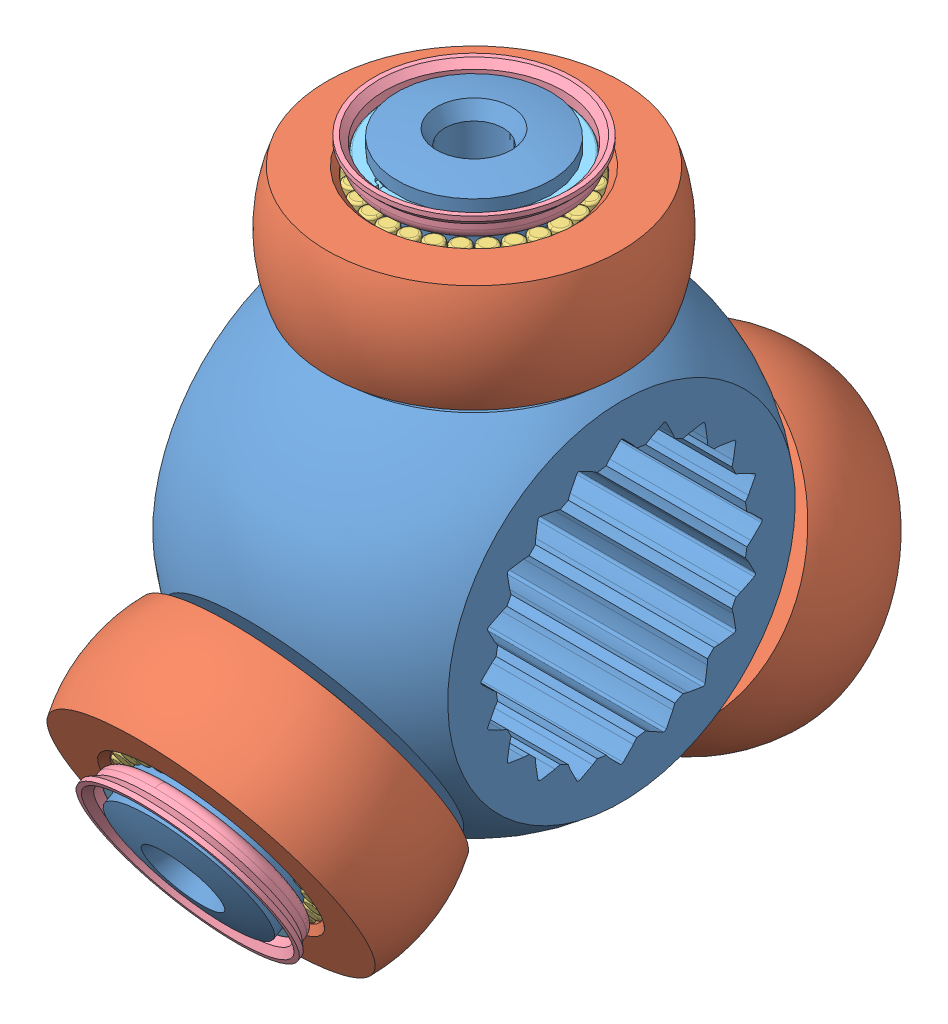
SolidWorks assembly Taylor INV-02002011, configuration Default. Lengths in mm.
Overall size (27.63 50.78 55.51).
97 component instances, 6 part files, 0 mates.
Components (placement in the parent):
- INV-020020111-1: INV-020020111 [Default] at origin size (24 46.21 53.88)
- INV-020020112-1: INV-020020112 [Default] at (0 20.32 0) x (0 -1 0) z (0 0 1) size (8.76 25.45 25.45)
- INV-020020116-1: INV-020020116 [Default] at (0 20.32 7.0097) x (0 0 1) z (-1 0 0) size (1.5 7.8 1.5)
- INV-020020116-2: INV-020020116 [Default] at (1.5598 20.32 6.834) x (0.222521 0 0.974928) z (-0.974928 0 0.222521) size (1.5 7.8 1.5)
- INV-020020116-3: INV-020020116 [Default] at (3.0414 20.32 6.3155) x (0.433884 0 0.900969) z (-0.900969 0 0.433884) size (1.5 7.8 1.5)
- INV-020020116-4: INV-020020116 [Default] at (4.3705 20.32 5.4804) x (0.62349 0 0.781831) z (-0.781831 0 0.62349) size (1.5 7.8 1.5)
- INV-020020116-5: INV-020020116 [Default] at (5.4804 20.32 4.3705) x (0.781831 0 0.62349) z (-0.62349 0 0.781831) size (1.5 7.8 1.5)
- INV-020020116-6: INV-020020116 [Default] at (6.3155 20.32 3.0414) x (0.900969 0 0.433884) z (-0.433884 0 0.900969) size (1.5 7.8 1.5)
- INV-020020116-7: INV-020020116 [Default] at (6.834 20.32 1.5598) x (0.974928 0 0.222521) z (-0.222521 0 0.974928) size (1.5 7.8 1.5)
- INV-020020116-8: INV-020020116 [Default] at (7.0097 20.32 0) size (1.5 7.8 1.5)
- INV-020020116-9: INV-020020116 [Default] at (6.834 20.32 -1.5598) x (0.974928 0 -0.222521) z (0.222521 0 0.974928) size (1.5 7.8 1.5)
- INV-020020116-10: INV-020020116 [Default] at (6.3155 20.32 -3.0414) x (0.900969 0 -0.433884) z (0.433884 0 0.900969) size (1.5 7.8 1.5)
- INV-020020116-11: INV-020020116 [Default] at (5.4804 20.32 -4.3705) x (0.781831 0 -0.62349) z (0.62349 0 0.781831) size (1.5 7.8 1.5)
- INV-020020116-12: INV-020020116 [Default] at (4.3705 20.32 -5.4804) x (0.62349 0 -0.781831) z (0.781831 0 0.62349) size (1.5 7.8 1.5)
- INV-020020116-13: INV-020020116 [Default] at (3.0414 20.32 -6.3155) x (0.433884 0 -0.900969) z (0.900969 0 0.433884) size (1.5 7.8 1.5)
- INV-020020116-14: INV-020020116 [Default] at (1.5598 20.32 -6.834) x (0.222521 0 -0.974928) z (0.974928 0 0.222521) size (1.5 7.8 1.5)
- INV-020020116-15: INV-020020116 [Default] at (0 20.32 -7.0097) x (0 0 -1) z (1 0 0) size (1.5 7.8 1.5)
- INV-020020116-16: INV-020020116 [Default] at (-1.5598 20.32 -6.834) x (-0.222521 0 -0.974928) z (0.974928 0 -0.222521) size (1.5 7.8 1.5)
- INV-020020116-17: INV-020020116 [Default] at (-3.0414 20.32 -6.3155) x (-0.433884 0 -0.900969) z (0.900969 0 -0.433884) size (1.5 7.8 1.5)
- INV-020020116-18: INV-020020116 [Default] at (-4.3705 20.32 -5.4804) x (-0.62349 0 -0.781831) z (0.781831 0 -0.62349) size (1.5 7.8 1.5)
- INV-020020116-19: INV-020020116 [Default] at (-5.4804 20.32 -4.3705) x (-0.781831 0 -0.62349) z (0.62349 0 -0.781831) size (1.5 7.8 1.5)
- INV-020020116-20: INV-020020116 [Default] at (-6.3155 20.32 -3.0414) x (-0.900969 0 -0.433884) z (0.433884 0 -0.900969) size (1.5 7.8 1.5)
- INV-020020116-21: INV-020020116 [Default] at (-6.834 20.32 -1.5598) x (-0.974928 0 -0.222521) z (0.222521 0 -0.974928) size (1.5 7.8 1.5)
- INV-020020116-22: INV-020020116 [Default] at (-7.0097 20.32 0) x (-1 0 0) z (0 0 -1) size (1.5 7.8 1.5)
- INV-020020116-23: INV-020020116 [Default] at (-6.834 20.32 1.5598) x (-0.974928 0 0.222521) z (-0.222521 0 -0.974928) size (1.5 7.8 1.5)
- INV-020020116-24: INV-020020116 [Default] at (-6.3155 20.32 3.0414) x (-0.900969 0 0.433884) z (-0.433884 0 -0.900969) size (1.5 7.8 1.5)
- INV-020020116-25: INV-020020116 [Default] at (-5.4804 20.32 4.3705) x (-0.781831 0 0.62349) z (-0.62349 0 -0.781831) size (1.5 7.8 1.5)
- INV-020020116-26: INV-020020116 [Default] at (-4.3705 20.32 5.4804) x (-0.62349 0 0.781831) z (-0.781831 0 -0.62349) size (1.5 7.8 1.5)
- INV-020020116-27: INV-020020116 [Default] at (-3.0414 20.32 6.3155) x (-0.433884 0 0.900969) z (-0.900969 0 -0.433884) size (1.5 7.8 1.5)
- INV-020020116-28: INV-020020116 [Default] at (-1.5598 20.32 6.834) x (-0.222521 0 0.974928) z (-0.974928 0 -0.222521) size (1.5 7.8 1.5)
- INV-020020113-1: INV-020020113 [Default] at (0 24.7396 0) size (16.26 2.16 16.26)
- WS_50-1-1: WS_50-1 [Default] at (0 25.4381 0) size (27.63 0.71 15.46)
- INV-020020116-29: INV-020020116 [Default] at (0 -4.0894 -21.1025) x (0 0.866025 -0.5) z (-1 0 0) size (1.5 7.8 1.5)
- INV-020020116-30: INV-020020116 [Default] at (0 -16.2306 14.0928) x (0 -0.866025 -0.5) z (-1 0 0) size (1.5 7.8 1.5)
- INV-020020113-2: INV-020020113 [Default] at (0 -12.3698 -21.4251) x (1 0 0) z (0 0.866025 -0.5) size (16.26 2.16 16.26)
- INV-020020113-3: INV-020020113 [Default] at (0 -12.3698 21.4251) x (1 0 0) z (0 -0.866025 -0.5) size (16.26 2.16 16.26)
- WS_50-1-2: WS_50-1 [Default] at (0 -12.7191 -22.03) x (1 0 0) z (0 0.866025 -0.5) size (27.63 0.71 15.46)
- WS_50-1-3: WS_50-1 [Default] at (0 -12.7191 22.03) x (1 0 0) z (0 -0.866025 -0.5) size (27.63 0.71 15.46)
- INV-020020116-31: INV-020020116 [Default] at (1.5598 -4.2416 -21.0146) x (0.222521 0.844312 -0.487464) z (-0.974928 0.192709 -0.11126) size (1.5 7.8 1.5)
- INV-020020116-32: INV-020020116 [Default] at (1.5598 -16.0784 14.1807) x (0.222521 -0.844312 -0.487464) z (-0.974928 -0.192709 -0.11126) size (1.5 7.8 1.5)
- INV-020020116-33: INV-020020116 [Default] at (3.0414 -4.6906 -20.7554) x (0.433884 0.780262 -0.450484) z (-0.900969 0.375754 -0.216942) size (1.5 7.8 1.5)
- INV-020020116-34: INV-020020116 [Default] at (3.0414 -15.6294 14.4399) x (0.433884 -0.780262 -0.450484) z (-0.900969 -0.375754 -0.216942) size (1.5 7.8 1.5)
- INV-020020116-35: INV-020020116 [Default] at (4.3705 -5.4138 -20.3378) x (0.62349 0.677086 -0.390916) z (-0.781831 0.539958 -0.311745) size (1.5 7.8 1.5)
- INV-020020116-36: INV-020020116 [Default] at (4.3705 -14.9062 14.8574) x (0.62349 -0.677086 -0.390916) z (-0.781831 -0.539958 -0.311745) size (1.5 7.8 1.5)
- INV-020020116-37: INV-020020116 [Default] at (5.4804 -6.3751 -19.7829) x (0.781831 0.539958 -0.311745) z (-0.62349 0.677086 -0.390916) size (1.5 7.8 1.5)
- INV-020020116-38: INV-020020116 [Default] at (5.4804 -13.9449 15.4124) x (0.781831 -0.539958 -0.311745) z (-0.62349 -0.677086 -0.390916) size (1.5 7.8 1.5)
- INV-020020116-39: INV-020020116 [Default] at (6.3155 -7.5261 -19.1183) x (0.900969 0.375754 -0.216942) z (-0.433884 0.780262 -0.450484) size (1.5 7.8 1.5)
- INV-020020116-40: INV-020020116 [Default] at (6.3155 -12.7939 16.0769) x (0.900969 -0.375754 -0.216942) z (-0.433884 -0.780262 -0.450484) size (1.5 7.8 1.5)
- INV-020020116-41: INV-020020116 [Default] at (6.834 -8.8092 -18.3775) x (0.974928 0.192709 -0.11126) z (-0.222521 0.844312 -0.487464) size (1.5 7.8 1.5)
- INV-020020116-42: INV-020020116 [Default] at (6.834 -11.5108 16.8177) x (0.974928 -0.192709 -0.11126) z (-0.222521 -0.844312 -0.487464) size (1.5 7.8 1.5)
- INV-020020116-43: INV-020020116 [Default] at (7.0097 -10.16 -17.5976) x (1 0 0) z (0 0.866025 -0.5) size (1.5 7.8 1.5)
- INV-020020116-44: INV-020020116 [Default] at (7.0097 -10.16 17.5976) x (1 0 0) z (0 -0.866025 -0.5) size (1.5 7.8 1.5)
- INV-020020116-45: INV-020020116 [Default] at (6.834 -11.5108 -16.8177) x (0.974928 -0.192709 0.11126) z (0.222521 0.844312 -0.487464) size (1.5 7.8 1.5)
- INV-020020116-46: INV-020020116 [Default] at (6.834 -8.8092 18.3775) x (0.974928 0.192709 0.11126) z (0.222521 -0.844312 -0.487464) size (1.5 7.8 1.5)
- INV-020020116-47: INV-020020116 [Default] at (6.3155 -12.7939 -16.0769) x (0.900969 -0.375754 0.216942) z (0.433884 0.780262 -0.450484) size (1.5 7.8 1.5)
- INV-020020116-48: INV-020020116 [Default] at (6.3155 -7.5261 19.1183) x (0.900969 0.375754 0.216942) z (0.433884 -0.780262 -0.450484) size (1.5 7.8 1.5)
- INV-020020116-49: INV-020020116 [Default] at (5.4804 -13.9449 -15.4124) x (0.781831 -0.539958 0.311745) z (0.62349 0.677086 -0.390916) size (1.5 7.8 1.5)
- INV-020020116-50: INV-020020116 [Default] at (5.4804 -6.3751 19.7829) x (0.781831 0.539958 0.311745) z (0.62349 -0.677086 -0.390916) size (1.5 7.8 1.5)
- INV-020020116-51: INV-020020116 [Default] at (4.3705 -14.9062 -14.8574) x (0.62349 -0.677086 0.390916) z (0.781831 0.539958 -0.311745) size (1.5 7.8 1.5)
- INV-020020116-52: INV-020020116 [Default] at (4.3705 -5.4138 20.3378) x (0.62349 0.677086 0.390916) z (0.781831 -0.539958 -0.311745) size (1.5 7.8 1.5)
- INV-020020116-53: INV-020020116 [Default] at (3.0414 -15.6294 -14.4399) x (0.433884 -0.780262 0.450484) z (0.900969 0.375754 -0.216942) size (1.5 7.8 1.5)
- INV-020020116-54: INV-020020116 [Default] at (3.0414 -4.6906 20.7554) x (0.433884 0.780262 0.450484) z (0.900969 -0.375754 -0.216942) size (1.5 7.8 1.5)
- INV-020020116-55: INV-020020116 [Default] at (1.5598 -16.0784 -14.1807) x (0.222521 -0.844312 0.487464) z (0.974928 0.192709 -0.11126) size (1.5 7.8 1.5)
- INV-020020116-56: INV-020020116 [Default] at (1.5598 -4.2416 21.0146) x (0.222521 0.844312 0.487464) z (0.974928 -0.192709 -0.11126) size (1.5 7.8 1.5)
- INV-020020116-57: INV-020020116 [Default] at (0 -16.2306 -14.0928) x (0 -0.866025 0.5) z (1 0 0) size (1.5 7.8 1.5)
- INV-020020116-58: INV-020020116 [Default] at (0 -4.0894 21.1025) x (0 0.866025 0.5) z (1 0 0) size (1.5 7.8 1.5)
- INV-020020116-59: INV-020020116 [Default] at (-1.5598 -16.0784 -14.1807) x (-0.222521 -0.844312 0.487464) z (0.974928 -0.192709 0.11126) size (1.5 7.8 1.5)
- INV-020020116-60: INV-020020116 [Default] at (-1.5598 -4.2416 21.0146) x (-0.222521 0.844312 0.487464) z (0.974928 0.192709 0.11126) size (1.5 7.8 1.5)
- INV-020020116-61: INV-020020116 [Default] at (-3.0414 -15.6294 -14.4399) x (-0.433884 -0.780262 0.450484) z (0.900969 -0.375754 0.216942) size (1.5 7.8 1.5)
- INV-020020116-62: INV-020020116 [Default] at (-3.0414 -4.6906 20.7554) x (-0.433884 0.780262 0.450484) z (0.900969 0.375754 0.216942) size (1.5 7.8 1.5)
- INV-020020116-63: INV-020020116 [Default] at (-4.3705 -14.9062 -14.8574) x (-0.62349 -0.677086 0.390916) z (0.781831 -0.539958 0.311745) size (1.5 7.8 1.5)
- INV-020020116-64: INV-020020116 [Default] at (-4.3705 -5.4138 20.3378) x (-0.62349 0.677086 0.390916) z (0.781831 0.539958 0.311745) size (1.5 7.8 1.5)
- INV-020020116-65: INV-020020116 [Default] at (-5.4804 -13.9449 -15.4124) x (-0.781831 -0.539958 0.311745) z (0.62349 -0.677086 0.390916) size (1.5 7.8 1.5)
- INV-020020116-66: INV-020020116 [Default] at (-5.4804 -6.3751 19.7829) x (-0.781831 0.539958 0.311745) z (0.62349 0.677086 0.390916) size (1.5 7.8 1.5)
- INV-020020116-67: INV-020020116 [Default] at (-6.3155 -12.7939 -16.0769) x (-0.900969 -0.375754 0.216942) z (0.433884 -0.780262 0.450484) size (1.5 7.8 1.5)
- INV-020020116-68: INV-020020116 [Default] at (-6.3155 -7.5261 19.1183) x (-0.900969 0.375754 0.216942) z (0.433884 0.780262 0.450484) size (1.5 7.8 1.5)
- INV-020020116-69: INV-020020116 [Default] at (-6.834 -11.5108 -16.8177) x (-0.974928 -0.192709 0.11126) z (0.222521 -0.844312 0.487464) size (1.5 7.8 1.5)
- INV-020020116-70: INV-020020116 [Default] at (-6.834 -8.8092 18.3775) x (-0.974928 0.192709 0.11126) z (0.222521 0.844312 0.487464) size (1.5 7.8 1.5)
- INV-020020116-71: INV-020020116 [Default] at (-7.0097 -10.16 -17.5976) x (-1 0 0) z (0 -0.866025 0.5) size (1.5 7.8 1.5)
- INV-020020116-72: INV-020020116 [Default] at (-7.0097 -10.16 17.5976) x (-1 0 0) z (0 0.866025 0.5) size (1.5 7.8 1.5)
- INV-020020116-73: INV-020020116 [Default] at (-6.834 -8.8092 -18.3775) x (-0.974928 0.192709 -0.11126) z (-0.222521 -0.844312 0.487464) size (1.5 7.8 1.5)
- INV-020020116-74: INV-020020116 [Default] at (-6.834 -11.5108 16.8177) x (-0.974928 -0.192709 -0.11126) z (-0.222521 0.844312 0.487464) size (1.5 7.8 1.5)
- INV-020020116-75: INV-020020116 [Default] at (-6.3155 -7.5261 -19.1183) x (-0.900969 0.375754 -0.216942) z (-0.433884 -0.780262 0.450484) size (1.5 7.8 1.5)
- INV-020020116-76: INV-020020116 [Default] at (-6.3155 -12.7939 16.0769) x (-0.900969 -0.375754 -0.216942) z (-0.433884 0.780262 0.450484) size (1.5 7.8 1.5)
- INV-020020116-77: INV-020020116 [Default] at (-5.4804 -6.3751 -19.7829) x (-0.781831 0.539958 -0.311745) z (-0.62349 -0.677086 0.390916) size (1.5 7.8 1.5)
- INV-020020116-78: INV-020020116 [Default] at (-5.4804 -13.9449 15.4124) x (-0.781831 -0.539958 -0.311745) z (-0.62349 0.677086 0.390916) size (1.5 7.8 1.5)
- INV-020020116-79: INV-020020116 [Default] at (-4.3705 -5.4138 -20.3378) x (-0.62349 0.677086 -0.390916) z (-0.781831 -0.539958 0.311745) size (1.5 7.8 1.5)
- INV-020020116-80: INV-020020116 [Default] at (-4.3705 -14.9062 14.8574) x (-0.62349 -0.677086 -0.390916) z (-0.781831 0.539958 0.311745) size (1.5 7.8 1.5)
- INV-020020116-81: INV-020020116 [Default] at (-3.0414 -4.6906 -20.7554) x (-0.433884 0.780262 -0.450484) z (-0.900969 -0.375754 0.216942) size (1.5 7.8 1.5)
- INV-020020116-82: INV-020020116 [Default] at (-3.0414 -15.6294 14.4399) x (-0.433884 -0.780262 -0.450484) z (-0.900969 0.375754 0.216942) size (1.5 7.8 1.5)
- INV-020020116-83: INV-020020116 [Default] at (-1.5598 -4.2416 -21.0146) x (-0.222521 0.844312 -0.487464) z (-0.974928 -0.192709 0.11126) size (1.5 7.8 1.5)
- INV-020020116-84: INV-020020116 [Default] at (-1.5598 -16.0784 14.1807) x (-0.222521 -0.844312 -0.487464) z (-0.974928 0.192709 0.11126) size (1.5 7.8 1.5)
- INV-020020112-2: INV-020020112 [Default] at (0 -10.16 -17.5976) x (0 0.5 0.866025) z (0 0.866025 -0.5) size (8.76 25.45 25.45)
- INV-020020112-3: INV-020020112 [Default] at (0 -10.16 17.5976) x (0 0.5 -0.866025) z (0 -0.866025 -0.5) size (8.76 25.45 25.45)
- INV-020020114-1: INV-020020114 [Default] at (0 16.2814 0) size (15.49 1.27 15.49)
- INV-020020114-2: INV-020020114 [Default] at (0 -8.1407 -14.1001) x (1 0 0) z (0 0.866025 -0.5) size (15.49 1.27 15.49)
- INV-020020114-3: INV-020020114 [Default] at (0 -8.1407 14.1001) x (1 0 0) z (0 -0.866025 -0.5) size (15.49 1.27 15.49)
